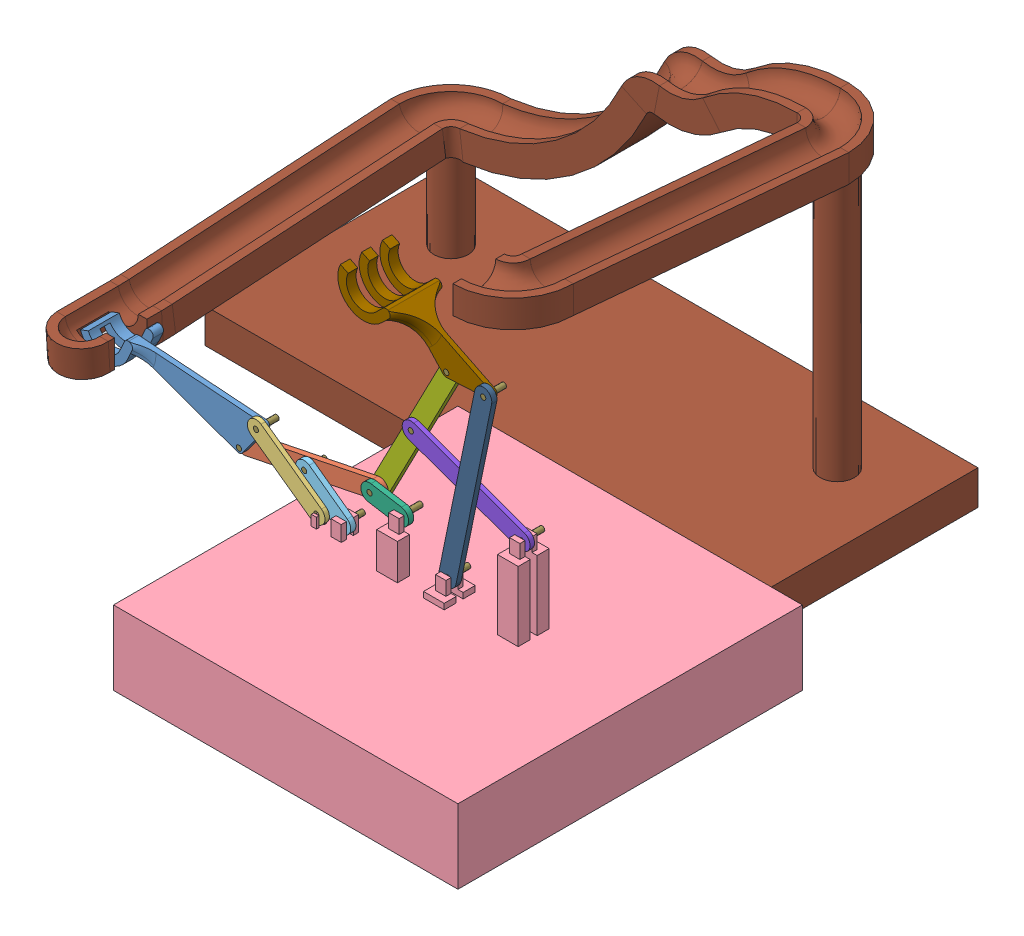
SolidWorks assembly 組合件1, configuration 預設. Lengths in mm.
Overall size (173.5 105 171.5).
23 component instances, 12 part files, 41 mates.
Components (placement in the parent):
- 第一大三角-1: 第一大三角 [預設] at (-94.7406 19.708 -1.27) x (0.997433 -0.071607 0) z (0 0 1) size (51.89 11.35 9.41)
- 38.69-1: 38.69 [預設] at (-45.1581 12.5023 -2.77) x (-0.979826 -0.199851 0) z (0 0 1) size (43.68 5 1.5)
- 21.59-1: 21.59 [預設] at (-49.1161 10.7814 0.115) x (-0.813273 0.581882 0) z (0 0 1) size (26.59 5 1.27)
- 大地板-1: 大地板 [預設] at origin size (100 45.67 100)
- 13.62-1: 13.62 [預設] at (-39.6475 8.5011 -1.27) x (-0.809197 0.587537 0) z (0 0 1) size (18.62 5 1.5)
- 8.99-1: 8.99 [預設] at (-21.7715 15.6339 -1.27) x (0.986582 -0.163268 0) z (0 0 1) size (13.99 5 1.5)
- 44.72-1: 44.72 [預設] at (-15.9069 36.2146 -4.27) x (0.460611 0.887602 0) z (0 0 1) size (49.72 5 1.5)
- 34.16-1: 34.16 [預設] at (0.1681 30.4423 -2.87) x (0.941162 -0.337955 0) z (0 0 1) size (39.16 5 1.3)
- 第二大三角-1: 第二大三角 [預設] at (-28.75 64.5789 -2.87) x (0.976137 -0.217158 0) z (0 0 1) size (41.11 13.47 16.35)
- 51.61-1: 51.61 [預設] at (1.4442 31.4295 -1.47) x (-0.200776 -0.979637 0) z (0 0 1) size (56.61 5 1.5)
- 軌道-1: 軌道 [預設] at (12 85 -14) size (153 105 131.99)
- 銷-1: 銷 [預設] at (-64.11 8.6367 -3.52) size (1.5 1.5 6)
- 銷-2: 銷 [預設] at (-57.8954 17.0628 -2.25) size (1.5 1.5 6)
- 銷-3: 銷 [預設] at (-26.2062 16.3678 -3.52) size (1.5 1.5 6)
- 銷-4: 銷 [預設] at (-40.3368 4.5 -2.25) size (1.5 1.5 6)
- 銷-5: 銷 [預設] at (-45.1581 12.5023 -3.52) size (1.5 1.5 6)
- 銷-6: 銷 [預設] at (-15.9069 36.2146 -5.22) size (1.5 1.5 6)
- 銷-7: 銷 [預設] at (-5.6077 56.0613 -5.22) size (1.5 1.5 6)
- 銷-8: 銷 [預設] at (6.6252 56.7091 -3.72) size (1.5 1.5 6)
- 銷-9: 銷 [預設] at (-34.1368 4.5 -3.52) size (1.5 1.5 6)
- 銷-10: 銷 [預設] at (-17.3368 14.9 -3.52) size (1.5 1.5 6)
- 銷-11: 銷 [預設] at (-3.7368 6.15 -3.72) size (1.5 1.5 6)
- 銷-12: 銷 [預設] at (16.2432 24.67 -5.22) size (1.5 1.5 6)
Mates (geometry in assembly coordinates):
- 同軸心3: concentric aligned: cylinder of 21.59-1 through (-40.3368 4.5 0.75) axis (0 0 -1) radius 0.75; cylinder of 大地板-1 through (-40.3368 4.5 0.75) axis (0 0 -1) radius 0.75
- 重合/共線/共點3: coincident anti-aligned: plane of 21.59-1 through (-40.3368 4.5 0.75) normal (0 0 1); plane of 大地板-1 through (0 0 0.75) normal (0 0 -1)
- 重合/共線/共點4: coincident anti-aligned: plane of 第一大三角-1 through (-94.7406 19.708 -0.52) normal (0 0 1); plane of 21.59-1 through (-40.3368 4.5 -0.52) normal (0 0 -1)
- 同軸心4: concentric anti-aligned: cylinder of 第一大三角-1 through (-57.8954 17.0628 -12.02) axis (0 0 1) radius 0.75; cylinder of 21.59-1 through (-57.8954 17.0628 0.75) axis (0 0 -1) radius 0.75
- 重合/共線/共點5: coincident anti-aligned: plane of 第一大三角-1 through (-94.7406 19.708 -2.02) normal (0 0 -1); plane of 38.69-1 through (-26.2062 16.3678 -2.02) normal (0 0 1)
- 同軸心5: concentric anti-aligned: cylinder of 第一大三角-1 through (-64.11 8.6367 -12.02) axis (0 0 1) radius 0.75; cylinder of 38.69-1 through (-64.11 8.6367 -2.02) axis (0 0 -1) radius 0.75
- 重合/共線/共點6: coincident anti-aligned: plane of 38.69-1 through (-26.2062 16.3678 -2.02) normal (0 0 1); plane of 13.62-1 through (-34.1368 4.5 -2.02) normal (0 0 -1)
- 同軸心6: concentric aligned: cylinder of 大地板-1 through (-34.1368 4.5 0.25) axis (0 0 -1) radius 0.75; cylinder of 13.62-1 through (-34.1368 4.5 -0.52) axis (0 0 -1) radius 0.75
- 同軸心7: concentric aligned: cylinder of 38.69-1 through (-45.1581 12.5023 -2.02) axis (0 0 -1) radius 0.75; cylinder of 13.62-1 through (-45.1581 12.5023 -0.52) axis (0 0 -1) radius 0.75
- 重合/共線/共點10: coincident anti-aligned: plane of 38.69-1 through (-26.2062 16.3678 -2.02) normal (0 0 1); plane of 8.99-1 through (-26.2062 16.3678 -2.02) normal (0 0 -1)
- 同軸心8: concentric aligned: cylinder of 38.69-1 through (-26.2062 16.3678 -2.02) axis (0 0 -1) radius 0.75; cylinder of 8.99-1 through (-26.2062 16.3678 -0.52) axis (0 0 -1) radius 0.75
- 同軸心9: concentric aligned: cylinder of 大地板-1 through (-17.3368 14.9 0.75) axis (0 0 -1) radius 0.75; cylinder of 8.99-1 through (-17.3368 14.9 -0.52) axis (0 0 -1) radius 0.75
- 重合/共線/共點11: coincident anti-aligned: plane of 38.69-1 through (-26.2062 16.3678 -3.52) normal (0 0 -1); plane of 44.72-1 through (-26.2062 16.3678 -3.52) normal (0 0 1)
- 同軸心10: concentric aligned: cylinder of 38.69-1 through (-26.2062 16.3678 -2.02) axis (0 0 -1) radius 0.75; cylinder of 44.72-1 through (-26.2062 16.3678 -3.52) axis (0 0 -1) radius 0.75
- 重合/共線/共點12: coincident anti-aligned: plane of 44.72-1 through (-26.2062 16.3678 -3.52) normal (0 0 1); plane of 34.16-1 through (-15.9069 36.2146 -3.52) normal (0 0 -1)
- 同軸心11: concentric aligned: cylinder of 44.72-1 through (-15.9069 36.2146 -3.52) axis (0 0 -1) radius 0.75; cylinder of 34.16-1 through (-15.9069 36.2146 -2.22) axis (0 0 -1) radius 0.75
- 同軸心12: concentric aligned: cylinder of 大地板-1 through (16.2432 24.67 0.3713) axis (0 0 -1) radius 0.75; cylinder of 34.16-1 through (16.2432 24.67 -2.22) axis (0 0 -1) radius 0.75
- 重合/共線/共點13: coincident anti-aligned: plane of 44.72-1 through (-26.2062 16.3678 -3.52) normal (0 0 1); plane of 第二大三角-1 through (6.6252 56.7091 -3.52) normal (0 0 -1)
- 同軸心13: concentric aligned: cylinder of 44.72-1 through (-5.6077 56.0613 -3.52) axis (0 0 -1) radius 0.75; cylinder of 第二大三角-1 through (-5.6077 56.0613 -2.22) axis (0 0 -1) radius 0.75
- 重合/共線/共點14: coincident anti-aligned: plane of 第二大三角-1 through (6.6252 56.7091 -2.22) normal (0 0 1); plane of 51.61-1 through (6.6252 56.7091 -2.22) normal (0 0 -1)
- 同軸心14: concentric aligned: cylinder of 第二大三角-1 through (6.6252 56.7091 -2.22) axis (0 0 -1) radius 0.75; cylinder of 51.61-1 through (6.6252 56.7091 -0.72) axis (0 0 -1) radius 0.75
- 同軸心15: concentric aligned: cylinder of 大地板-1 through (-3.7368 6.15 0.75) axis (0 0 -1) radius 0.75; cylinder of 51.61-1 through (-3.7368 6.15 -0.72) axis (0 0 -1) radius 0.75
- 重合/共線/共點15: coincident aligned: plane of 大地板-1 through (0 0 0) normal (0 1 0); plane of assembly through (0 0 0) normal (0 1 0)
- 重合/共線/共點16: coincident aligned: plane of 大地板-1 through (0 0 0) normal (0 0 1); plane of assembly through (0 0 0) normal (0 0 1)
- 重合/共線/共點17: coincident aligned: plane of 大地板-1 through (0 0 0) normal (1 0 0); plane of assembly through (0 0 0) normal (1 0 0)
- 平行相距2: distance = 85 mm aligned: plane of assembly through (0 0 0) normal (0 1 0); plane of 軌道-1 through (12 85 -14) normal (0 1 0)
- 平行相距3: distance = 14 mm aligned: plane of assembly through (0 0 0) normal (0 0 1); plane of 軌道-1 through (12 85 -14) normal (0 0 1)
- 平行相距4: distance = 12 mm aligned: plane of assembly through (0 0 0) normal (1 0 0); plane of 軌道-1 through (12 85 -14) normal (1 0 0)
- 重合/共線/共點21: coincident aligned: plane of 第一大三角-1 through (-94.7406 19.708 -0.52) normal (0 0 1); plane of 銷-1 through (-64.11 8.6367 -0.52) normal (0 0 1)
- 重合/共線/共點22: coincident aligned: circle of 第一大三角-1; circle of 銷-1
- 重合/共線/共點24: coincident aligned: circle of 21.59-1; circle of 銷-2
- 重合/共線/共點26: coincident aligned: circle of 13.62-1; circle of 銷-5
- 重合/共線/共點27: coincident aligned: circle of 8.99-1; circle of 銷-3
- 重合/共線/共點28: coincident aligned: circle of 34.16-1; circle of 銷-6
- 重合/共線/共點29: coincident aligned: circle of 第二大三角-1; circle of 銷-7
- 重合/共線/共點30: coincident aligned: circle of 51.61-1; circle of 銷-8
- 重合/共線/共點31: coincident aligned: circle of 大地板-1; circle of 銷-4
- 重合/共線/共點32: coincident aligned: circle of 13.62-1; circle of 銷-9
- 重合/共線/共點33: coincident aligned: circle of 8.99-1; circle of 銷-10
- 重合/共線/共點34: coincident aligned: circle of 51.61-1; circle of 銷-11
- 重合/共線/共點35: coincident aligned: circle of 34.16-1; circle of 銷-12
